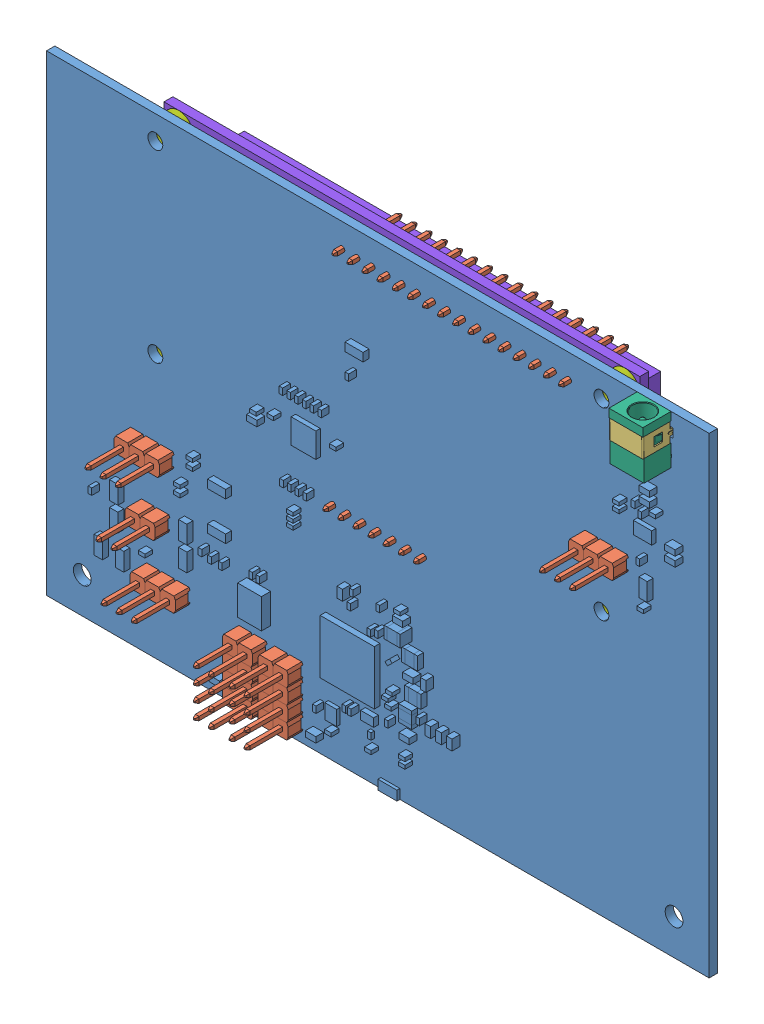
SolidWorks assembly PCB ASSY, configuration Default. Lengths in mm.
Overall size (111.4 79.3 20.98).
61 component instances, 8 part files, 26 mates.
Components (placement in the parent):
- pcb-1: pcb [Default] at (-55.2553 -31.6918 89.0126) size (111.4 79.3 4.54)
- pin header double row- 20 contacts-2: pin header double row- 20 contacts [Default] at (31.3735 92.5733 87.6126) x (1 0 0) z (0 1 0) size (2.54 11.54 2.54)
- pin header double row- 20 contacts-28: pin header double row- 20 contacts [Default] at (33.9135 92.5733 87.6126) x (1 0 0) z (0 1 0) size (2.54 11.54 2.54)
- pin header double row- 20 contacts-29: pin header double row- 20 contacts [Default] at (36.4535 92.5733 87.6126) x (1 0 0) z (0 1 0) size (2.54 11.54 2.54)
- pin header double row- 20 contacts-30: pin header double row- 20 contacts [Default] at (38.9935 92.5733 87.6126) x (1 0 0) z (0 1 0) size (2.54 11.54 2.54)
- pin header double row- 20 contacts-31: pin header double row- 20 contacts [Default] at (41.5335 92.5733 87.6126) x (1 0 0) z (0 1 0) size (2.54 11.54 2.54)
- pin header double row- 20 contacts-32: pin header double row- 20 contacts [Default] at (44.0735 92.5733 87.6126) x (1 0 0) z (0 1 0) size (2.54 11.54 2.54)
- pin header double row- 20 contacts-33: pin header double row- 20 contacts [Default] at (46.6135 92.5733 87.6126) x (1 0 0) z (0 1 0) size (2.54 11.54 2.54)
- pin header double row- 20 contacts-34: pin header double row- 20 contacts [Default] at (49.1535 92.5733 87.6126) x (1 0 0) z (0 1 0) size (2.54 11.54 2.54)
- pin header double row- 20 contacts-35: pin header double row- 20 contacts [Default] at (51.6935 92.5733 87.6126) x (1 0 0) z (0 1 0) size (2.54 11.54 2.54)
- pin header double row- 20 contacts-36: pin header double row- 20 contacts [Default] at (54.2335 92.5733 87.6126) x (1 0 0) z (0 1 0) size (2.54 11.54 2.54)
- pin header double row- 20 contacts-37: pin header double row- 20 contacts [Default] at (56.7735 92.5733 87.6126) x (1 0 0) z (0 1 0) size (2.54 11.54 2.54)
- pin header double row- 20 contacts-38: pin header double row- 20 contacts [Default] at (59.3135 92.5733 87.6126) x (1 0 0) z (0 1 0) size (2.54 11.54 2.54)
- pin header double row- 20 contacts-39: pin header double row- 20 contacts [Default] at (61.8535 92.5733 87.6126) x (1 0 0) z (0 1 0) size (2.54 11.54 2.54)
- pin header double row- 20 contacts-40: pin header double row- 20 contacts [Default] at (64.3935 92.5733 87.6126) x (1 0 0) z (0 1 0) size (2.54 11.54 2.54)
- pin header double row- 20 contacts-41: pin header double row- 20 contacts [Default] at (66.9335 92.5733 87.6126) x (1 0 0) z (0 1 0) size (2.54 11.54 2.54)
- pin header double row- 20 contacts-42: pin header double row- 20 contacts [Default] at (69.4735 92.5733 87.6126) x (1 0 0) z (0 1 0) size (2.54 11.54 2.54)
- pj-072c-smt-1: pj-072c-smt [Default] at (85.4947 95.3082 91.3126) x (-1 0 0) z (0 1 0) size (5.8 5.75 10.4)
  - pj-072c-smt_01-1: pj-072c-smt_01 [Default] at origin size (5.8 5.75 3.2)
  - pj-072c-smt_02-1: pj-072c-smt_02 [Default] at origin size (1.2 3 3.2)
  - pj-072c-smt_03-1: pj-072c-smt_03 [Default] at origin size (1.45 4.4 3.2)
  - pj-072c-smt_04-1: pj-072c-smt_04 [Default] at origin size (5.7 5.75 9.6)
- LCD spacer-1: LCD spacer [Default] at (76.2447 91.3082 87.6126) x (0 1 0) z (-1 0 0) size (5 2.54 5)
- LCD spacer-2: LCD spacer [Default] at (76.2447 60.3082 85.0726) x (1 0 0) z (0 -1 0) size (5 2.54 5)
- LCD spacer-3: LCD spacer [Default] at (1.2447 60.3082 85.0726) x (1 0 0) z (0 -1 0) size (5 2.54 5)
- LCD spacer-4: LCD spacer [Default] at (1.2447 91.3082 85.0726) x (1 0 0) z (0 -1 0) size (5 2.54 5)
- 16x2 Lcd display dsgn arch 2016-edit-00-1: 16x2 Lcd display dsgn arch 2016-edit-00 [Default] at (38.7447 75.8082 83.5726) x (1 0 0) z (0 0 -1) size (80 36 8.5)
- pin header double row- 20 contacts-43: pin header double row- 20 contacts [Default] at (45.0911 54.5782 87.6126) x (1 0 0) z (0 1 0) size (2.54 11.54 2.54)
- pin header double row- 20 contacts-44: pin header double row- 20 contacts [Default] at (42.5511 54.5782 87.6126) x (1 0 0) z (0 1 0) size (2.54 11.54 2.54)
- pin header double row- 20 contacts-45: pin header double row- 20 contacts [Default] at (40.0111 54.5782 87.6126) x (1 0 0) z (0 1 0) size (2.54 11.54 2.54)
- pin header double row- 20 contacts-46: pin header double row- 20 contacts [Default] at (37.4711 54.5782 87.6126) x (1 0 0) z (0 1 0) size (2.54 11.54 2.54)
- pin header double row- 20 contacts-47: pin header double row- 20 contacts [Default] at (34.9311 54.5782 87.6126) x (1 0 0) z (0 1 0) size (2.54 11.54 2.54)
- pin header double row- 20 contacts-48: pin header double row- 20 contacts [Default] at (32.3911 54.5782 87.6126) x (1 0 0) z (0 1 0) size (2.54 11.54 2.54)
- pin header double row- 20 contacts-49: pin header double row- 20 contacts [Default] at (29.8511 54.5782 87.6126) x (1 0 0) z (0 1 0) size (2.54 11.54 2.54)
- pin header double row- 20 contacts-50: pin header double row- 20 contacts [Default] at (-3.1653 45.0418 89.0126) x (1 0 0) z (0 -1 0) size (2.54 11.54 2.54)
- pin header double row- 20 contacts-51: pin header double row- 20 contacts [Default] at (-1.3422 35.5094 89.0126) x (1 0 0) z (0 -1 0) size (2.54 11.54 2.54)
- pin header double row- 20 contacts-52: pin header double row- 20 contacts [Default] at (-0.4792 26.6283 89.0126) x (1 0 0) z (0 -1 0) size (2.54 11.54 2.54)
- pin header double row- 20 contacts-53: pin header double row- 20 contacts [Default] at (17.5747 25.2818 89.0126) x (1 0 0) z (0 -1 0) size (2.54 11.54 2.54)
- pin header double row- 20 contacts-54: pin header double row- 20 contacts [Default] at (21.0383 25.2782 89.0126) x (1 0 0) z (0 -1 0) size (2.54 11.54 2.54)
- pin header double row- 20 contacts-55: pin header double row- 20 contacts [Default] at (-0.6253 45.0418 89.0126) x (1 0 0) z (0 -1 0) size (2.54 11.54 2.54)
- pin header double row- 20 contacts-56: pin header double row- 20 contacts [Default] at (1.9147 45.0418 89.0126) x (1 0 0) z (0 -1 0) size (2.54 11.54 2.54)
- pin header double row- 20 contacts-57: pin header double row- 20 contacts [Default] at (1.1978 35.5094 89.0126) x (1 0 0) z (0 -1 0) size (2.54 11.54 2.54)
- pin header double row- 20 contacts-58: pin header double row- 20 contacts [Default] at (2.0608 26.6283 89.0126) x (1 0 0) z (0 -1 0) size (2.54 11.54 2.54)
- pin header double row- 20 contacts-59: pin header double row- 20 contacts [Default] at (4.6008 26.6283 89.0126) x (1 0 0) z (0 -1 0) size (2.54 11.54 2.54)
- pin header double row- 20 contacts-60: pin header double row- 20 contacts [Default] at (23.5783 25.2782 89.0126) x (1 0 0) z (0 -1 0) size (2.54 11.54 2.54)
- pin header double row- 20 contacts-61: pin header double row- 20 contacts [Default] at (21.0383 22.7382 89.0126) x (1 0 0) z (0 -1 0) size (2.54 11.54 2.54)
- pin header double row- 20 contacts-62: pin header double row- 20 contacts [Default] at (23.5783 22.7382 89.0126) x (1 0 0) z (0 -1 0) size (2.54 11.54 2.54)
- pin header double row- 20 contacts-63: pin header double row- 20 contacts [Default] at (21.0383 20.1982 89.0126) x (1 0 0) z (0 -1 0) size (2.54 11.54 2.54)
- pin header double row- 20 contacts-64: pin header double row- 20 contacts [Default] at (23.5783 20.1982 89.0126) x (1 0 0) z (0 -1 0) size (2.54 11.54 2.54)
- pin header double row- 20 contacts-65: pin header double row- 20 contacts [Default] at (21.0383 17.6582 89.0126) x (1 0 0) z (0 -1 0) size (2.54 11.54 2.54)
- pin header double row- 20 contacts-66: pin header double row- 20 contacts [Default] at (23.5783 17.6582 89.0126) x (1 0 0) z (0 -1 0) size (2.54 11.54 2.54)
- pin header double row- 20 contacts-67: pin header double row- 20 contacts [Default] at (15.0347 25.2818 89.0126) x (1 0 0) z (0 -1 0) size (2.54 11.54 2.54)
- pin header double row- 20 contacts-68: pin header double row- 20 contacts [Default] at (17.5747 22.7418 89.0126) x (1 0 0) z (0 -1 0) size (2.54 11.54 2.54)
- pin header double row- 20 contacts-69: pin header double row- 20 contacts [Default] at (15.0347 22.7418 89.0126) x (1 0 0) z (0 -1 0) size (2.54 11.54 2.54)
- pin header double row- 20 contacts-70: pin header double row- 20 contacts [Default] at (17.5747 20.2018 89.0126) x (1 0 0) z (0 -1 0) size (2.54 11.54 2.54)
- pin header double row- 20 contacts-71: pin header double row- 20 contacts [Default] at (15.0347 20.2018 89.0126) x (1 0 0) z (0 -1 0) size (2.54 11.54 2.54)
- pin header double row- 20 contacts-72: pin header double row- 20 contacts [Default] at (17.5747 17.6618 89.0126) x (1 0 0) z (0 -1 0) size (2.54 11.54 2.54)
- pin header double row- 20 contacts-73: pin header double row- 20 contacts [Default] at (15.0347 17.6618 89.0126) x (1 0 0) z (0 -1 0) size (2.54 11.54 2.54)
- pin header double row- 20 contacts-74: pin header double row- 20 contacts [Default] at (78.3029 68.2428 89.0126) x (1 0 0) z (0 -1 0) size (2.54 11.54 2.54)
- pin header double row- 20 contacts-75: pin header double row- 20 contacts [Default] at (75.7629 68.2428 89.0126) x (1 0 0) z (0 -1 0) size (2.54 11.54 2.54)
- pin header double row- 20 contacts-76: pin header double row- 20 contacts [Default] at (73.2229 68.2428 89.0126) x (1 0 0) z (0 -1 0) size (2.54 11.54 2.54)
Mates (geometry in assembly coordinates):
- Coincident4: coincident: cylinder of pcb-1 through (70.7447 91.3082 87.6126) axis (0 0 -1) radius 0.45; line of pin header double row- 20 contacts-42 through (70.4235 91.6233 90.1046) axis (0 0 -1)
- Coincident5: coincident anti-aligned: plane of pcb-1 through (-17.0553 16.0082 87.6126) normal (0 0 -1); plane of pin header double row- 20 contacts-42 through (69.4735 92.5733 87.6126) normal (0 0 1)
- Concentric3: concentric aligned: circle of pcb-1; circle of pj-072c-smt-1/pj-072c-smt_04-1
- Coincident6: coincident anti-aligned: plane of pcb-1 through (-17.0553 16.0082 89.0126) normal (0 0 1); plane of pj-072c-smt-1/pj-072c-smt_04-1 through (87.9447 87.1082 89.0126) normal (0 0 -1)
- Coincident7: coincident anti-aligned: circle of pcb-1; circle of LCD spacer-1
- Coincident8: coincident aligned: circle of pcb-1; circle of LCD spacer-2
- Coincident9: coincident aligned: circle of pcb-1; circle of LCD spacer-4
- Coincident10: coincident aligned: circle of pcb-1; circle of LCD spacer-3
- Concentric4: concentric anti-aligned: circle of LCD spacer-1; circle of 16x2 Lcd display dsgn arch 2016-edit-00-1
- Coincident15: coincident: cylinder of pcb-1 through (38.7447 53.3082 87.6126) axis (0 0 -1) radius 0.45; line of pin header double row- 20 contacts-46 through (39.0611 53.6282 90.1046) axis (0 0 -1)
- Coincident18: coincident: cylinder of pcb-1 through (38.7447 53.3082 87.6126) axis (0 0 -1) radius 0.45; line of pin header double row- 20 contacts-46 through (39.0611 52.9882 90.1046) axis (0 0 -1)
- Coincident19: coincident anti-aligned: plane of pcb-1 through (-17.0553 16.0082 87.6126) normal (0 0 -1); plane of pin header double row- 20 contacts-45 through (40.0111 54.5782 87.6126) normal (0 0 1)
- Coincident20: coincident: cylinder of pcb-1 through (5.8847 27.9082 87.6126) axis (0 0 -1) radius 0.45; line of pin header double row- 20 contacts-59 through (6.1908 27.5783 86.5206) axis (0 0 1)
- Coincident23: coincident anti-aligned: plane of pcb-1 through (-17.0553 16.0082 89.0126) normal (0 0 1); plane of pin header double row- 20 contacts-59 through (4.6008 26.6283 89.0126) normal (0 0 -1)
- Coincident24: coincident: cylinder of pcb-1 through (2.4447 36.8082 87.6126) axis (0 0 -1) radius 0.45; line of pin header double row- 20 contacts-57 through (2.7878 37.0994 86.5206) axis (0 0 1)
- Coincident25: coincident anti-aligned: plane of pcb-1 through (-17.0553 16.0082 89.0126) normal (0 0 1); plane of pin header double row- 20 contacts-57 through (1.1978 35.5094 89.0126) normal (0 0 -1)
- Coincident26: coincident: cylinder of pcb-1 through (3.1847 46.3082 87.6126) axis (0 0 -1) radius 0.45; line of pin header double row- 20 contacts-56 through (2.8647 45.9918 86.5206) axis (0 0 1)
- Coincident27: coincident: cylinder of pcb-1 through (3.1847 46.3082 87.6126) axis (0 0 -1) radius 0.45; line of pin header double row- 20 contacts-56 through (3.5047 45.9918 86.5206) axis (0 0 1)
- Coincident28: coincident anti-aligned: plane of pcb-1 through (-17.0553 16.0082 89.0126) normal (0 0 1); plane of pin header double row- 20 contacts-56 through (1.9147 45.0418 89.0126) normal (0 0 -1)
- Coincident29: coincident: cylinder of pcb-1 through (22.3047 21.4682 87.6126) axis (0 0 -1) radius 0.45; line of pin header double row- 20 contacts-63 through (21.9883 21.1482 86.5206) axis (0 0 1)
- Coincident30: coincident: cylinder of pcb-1 through (22.3047 21.4682 87.6126) axis (0 0 -1) radius 0.45; line of pin header double row- 20 contacts-63 through (21.9883 21.7882 86.5206) axis (0 0 1)
- Coincident31: coincident anti-aligned: plane of pcb-1 through (-17.0553 16.0082 89.0126) normal (0 0 1); plane of pin header double row- 20 contacts-63 through (21.0383 20.1982 89.0126) normal (0 0 -1)
- Coincident33: coincident: cylinder of pcb-1 through (16.3047 18.9282 87.6126) axis (0 0 -1) radius 0.45; line of pin header double row- 20 contacts-73 through (15.9847 18.6118 86.5206) axis (0 0 1)
- Coincident34: coincident: cylinder of pcb-1 through (16.3047 18.9282 87.6126) axis (0 0 -1) radius 0.45; line of pin header double row- 20 contacts-73 through (16.6247 18.6118 86.5206) axis (0 0 1)
- Parallel7: parallel anti-aligned: cylinder of pcb-1 through (79.5847 69.5082 87.6126) axis (0 0 -1) radius 0.45; line of pin header double row- 20 contacts-74 through (79.2529 69.8328 86.5206) axis (0 0 1)
- Coincident51: coincident anti-aligned: plane of pcb-1 through (-17.0553 16.0082 89.0126) normal (0 0 1); plane of pin header double row- 20 contacts-75 through (75.7629 68.2428 89.0126) normal (0 0 -1)
